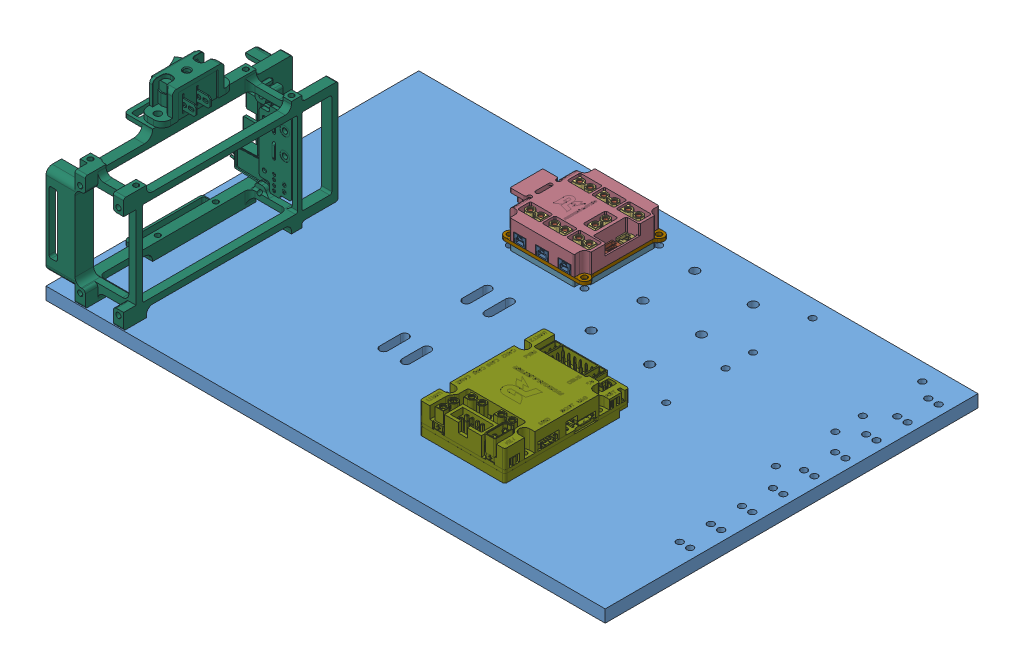
SolidWorks assembly 电气板, configuration 默认. Lengths in mm.
Overall size (270 75.31 180).
56 component instances, 16 part files, 9 mates.
Components (placement in the parent):
- 底板-2: 底板 [Default] at (214.7174 89.9924 227.1815) size (270 6 180)
- RM_ESC_Center_Board2.stp-1: RM_ESC_Center_Board2.stp [Default] at (192.7174 98.9924 170.1815) x (0 0 1) z (-1 0 0) size (41 14.11 48.51)
  - XT30UPB-F_3D_DRAWING_ASM.stp-1: XT30UPB-F_3D_DRAWING_ASM.stp [Default] at (-11.9 1.6 11.7) x (0 0 -1) z (0 1 0) size (10.2 5.6 12.4)
    - XT30UPB-F_ASM.stp-1: XT30UPB-F_ASM.stp [Default] at origin size (10.2 5.6 12.4)
      - MR30PB-F__.stp-1: MR30PB-F__.stp [Default] at (-2.5 0 7.9) x (-0.575428 -0.817853 0) z (0 0 -1) size (2.5 2.51 11.9)
      - XT30UPB-F_SJ.stp-1: XT30UPB-F_SJ.stp [Default] at origin size (10.2 5.6 9.4)
      - MR30PB-F__.stp-2: MR30PB-F__.stp [Default] at (2.5 0 7.9) x (-0.681294 -0.73201 0) z (0 0 -1) size (2.5 2.51 11.9)
  - XT30UPB-F_3D_DRAWING_ASM.stp-2: XT30UPB-F_3D_DRAWING_ASM.stp [Default] at (-11.9 1.6 0) x (0 0 -1) z (0 1 0) size (10.2 5.6 12.4)
    - XT30UPB-F_ASM.stp-1: XT30UPB-F_ASM.stp [Default] at origin size (10.2 5.6 12.4)
      - MR30PB-F__.stp-1: MR30PB-F__.stp [Default] at (-2.5 0 7.9) x (-0.575428 -0.817853 0) z (0 0 -1) size (2.5 2.51 11.9)
      - XT30UPB-F_SJ.stp-1: XT30UPB-F_SJ.stp [Default] at origin size (10.2 5.6 9.4)
      - MR30PB-F__.stp-2: MR30PB-F__.stp [Default] at (2.5 0 7.9) x (-0.681294 -0.73201 0) z (0 0 -1) size (2.5 2.51 11.9)
  - XT30UPB-F_3D_DRAWING_ASM.stp-3: XT30UPB-F_3D_DRAWING_ASM.stp [Default] at (-11.9 1.6 -11.7) x (0 0 -1) z (0 1 0) size (10.2 5.6 12.4)
    - XT30UPB-F_ASM.stp-1: XT30UPB-F_ASM.stp [Default] at origin size (10.2 5.6 12.4)
      - MR30PB-F__.stp-1: MR30PB-F__.stp [Default] at (-2.5 0 7.9) x (-0.575428 -0.817853 0) z (0 0 -1) size (2.5 2.51 11.9)
      - XT30UPB-F_SJ.stp-1: XT30UPB-F_SJ.stp [Default] at origin size (10.2 5.6 9.4)
      - MR30PB-F__.stp-2: MR30PB-F__.stp [Default] at (2.5 0 7.9) x (-0.681294 -0.73201 0) z (0 0 -1) size (2.5 2.51 11.9)
  - XT30UPB-F_3D_DRAWING_ASM.stp-4: XT30UPB-F_3D_DRAWING_ASM.stp [Default] at (11.9 1.6 11.7) x (0 0 1) z (0 1 0) size (10.2 5.6 12.4)
    - XT30UPB-F_ASM.stp-1: XT30UPB-F_ASM.stp [Default] at origin size (10.2 5.6 12.4)
      - MR30PB-F__.stp-1: MR30PB-F__.stp [Default] at (-2.5 0 7.9) x (-0.575428 -0.817853 0) z (0 0 -1) size (2.5 2.51 11.9)
      - XT30UPB-F_SJ.stp-1: XT30UPB-F_SJ.stp [Default] at origin size (10.2 5.6 9.4)
      - MR30PB-F__.stp-2: MR30PB-F__.stp [Default] at (2.5 0 7.9) x (-0.681294 -0.73201 0) z (0 0 -1) size (2.5 2.51 11.9)
  - XT30UPB-F_3D_DRAWING_ASM.stp-5: XT30UPB-F_3D_DRAWING_ASM.stp [Default] at (11.9 1.6 0) x (0 0 1) z (0 1 0) size (10.2 5.6 12.4)
    - XT30UPB-F_ASM.stp-1: XT30UPB-F_ASM.stp [Default] at origin size (10.2 5.6 12.4)
      - MR30PB-F__.stp-1: MR30PB-F__.stp [Default] at (-2.5 0 7.9) x (-0.575428 -0.817853 0) z (0 0 -1) size (2.5 2.51 11.9)
      - XT30UPB-F_SJ.stp-1: XT30UPB-F_SJ.stp [Default] at origin size (10.2 5.6 9.4)
      - MR30PB-F__.stp-2: MR30PB-F__.stp [Default] at (2.5 0 7.9) x (-0.681294 -0.73201 0) z (0 0 -1) size (2.5 2.51 11.9)
  - XT30UPB-F_3D_DRAWING_ASM.stp-6: XT30UPB-F_3D_DRAWING_ASM.stp [Default] at (11.9 1.6 -11.7) x (0 0 1) z (0 1 0) size (10.2 5.6 12.4)
    - XT30UPB-F_ASM.stp-1: XT30UPB-F_ASM.stp [Default] at origin size (10.2 5.6 12.4)
      - MR30PB-F__.stp-1: MR30PB-F__.stp [Default] at (-2.5 0 7.9) x (-0.575428 -0.817853 0) z (0 0 -1) size (2.5 2.51 11.9)
      - XT30UPB-F_SJ.stp-1: XT30UPB-F_SJ.stp [Default] at origin size (10.2 5.6 9.4)
      - MR30PB-F__.stp-2: MR30PB-F__.stp [Default] at (2.5 0 7.9) x (-0.681294 -0.73201 0) z (0 0 -1) size (2.5 2.51 11.9)
  - XT60_____ASM.stp-1: XT60_____ASM.stp [Default] at (0 5.65 40.6279) x (-1 0 0) z (0 0 -1) size (15.9 10.5 18.64)
    - XT60____-8________-2-SOLID1.stp-1: XT60____-8________-2-SOLID1.stp [Default] at origin size (0.5 9.4 2.2)
    - XT60____-8____-21157-2-SOLID1.stp-1: XT60____-8____-21157-2-SOLID1.stp [Default] at origin size (4.3 8.5 17.06)
    - XT60____-8______-UL-21156-1-SOL.stp-1: XT60____-8______-UL-21156-1-SOL.stp [Default] at origin size (15.9 8.45 18.2)
    - XT60____-8____-21157-1-SOLID1.stp-1: XT60____-8____-21157-1-SOLID1.stp [Default] at origin size (4.3 8.5 17.06)
    - XT60____-8________-1-SOLID1.stp-1: XT60____-8________-1-SOLID1.stp [Default] at origin size (0.5 9.4 2.2)
  - XT30UPB-F_3D_DRAWING_ASM.stp-7: XT30UPB-F_3D_DRAWING_ASM.stp [Default] at (0 1.6 -7.7) x (-1 0 0) z (0 1 0) size (10.2 5.6 12.4)
    - XT30UPB-F_ASM.stp-1: XT30UPB-F_ASM.stp [Default] at origin size (10.2 5.6 12.4)
      - MR30PB-F__.stp-1: MR30PB-F__.stp [Default] at (-2.5 0 7.9) x (-0.575428 -0.817853 0) z (0 0 -1) size (2.5 2.51 11.9)
      - XT30UPB-F_SJ.stp-1: XT30UPB-F_SJ.stp [Default] at origin size (10.2 5.6 9.4)
      - MR30PB-F__.stp-2: MR30PB-F__.stp [Default] at (2.5 0 7.9) x (-0.681294 -0.73201 0) z (0 0 -1) size (2.5 2.51 11.9)
  - CENTER_DISTRIBUTION_BOARD.stp-1: CENTER_DISTRIBUTION_BOARD.stp [Default] at origin size (41 1.62 41)
  - SM02B-GHS-TB.stp-1: SM02B-GHS-TB.stp [Default] at (-16.45 1.6 13.625) x (0 0 1) z (-1 0 0) size (5.75 4.35 4.85)
  - SM02B-GHS-TB.stp-2: SM02B-GHS-TB.stp [Default] at (-16.45 1.6 2.875) x (0 0 1) z (-1 0 0) size (5.75 4.35 4.85)
  - SM02B-GHS-TB.stp-3: SM02B-GHS-TB.stp [Default] at (-16.45 1.6 -7.875) x (0 0 1) z (-1 0 0) size (5.75 4.35 4.85)
  - SM02B-GHS-TB.stp-4: SM02B-GHS-TB.stp [Default] at (16.45 1.6 -13.625) x (0 0 -1) z (1 0 0) size (5.75 4.35 4.85)
  - SM02B-GHS-TB.stp-5: SM02B-GHS-TB.stp [Default] at (16.45 1.6 -2.875) x (0 0 -1) z (1 0 0) size (5.75 4.35 4.85)
  - SM02B-GHS-TB.stp-6: SM02B-GHS-TB.stp [Default] at (16.45 1.6 7.875) x (0 0 -1) z (1 0 0) size (5.75 4.35 4.85)
  - BM04B-GHS-TBT.stp-1: BM04B-GHS-TBT.stp [Default] at (7.5 1.775 -16.775) size (8.25 4.2 4.95)
  - BM02B-GHS-TBT.stp-1: BM02B-GHS-TBT.stp [Default] at (-1.75 1.775 -16.775) size (5.75 4.2 4.95)
  - SHELL_UP.stp-1: SHELL_UP.stp [Default] at (0 11.1 0.005) x (0 0 -1) z (-1 0 0) size (46.5 11.16 41)
  - SHELL_DOWN.stp-1: SHELL_DOWN.stp [Default] at (0 5 0.005) size (41 3 37)
- RoboMaster 电池架.step-1: RoboMaster 电池架.step [Default] at (90.2174 123.6924 311.1815) x (0 0 -1) z (0 1 0) size (103.5 37.5 69.31)
- mounting_the_board_type_c_asm(202001072134)-1: mounting_the_board_type_c_asm(202001072134) [Default] at (277.3177 116.5924 280.8614) x (1 0 0) z (0 1 0) size (41.04 60.33 16.3)
Mates (geometry in assembly coordinates):
- Coincident1: coincident anti-aligned: plane of 底板-2 through (214.7174 95.9924 227.1815) normal (0 1 0); plane of RM_ESC_Center_Board2.stp-1/SHELL_DOWN.stp-1 through (192.7124 95.9924 170.1815) normal (0 -1 0)
- Coincident2: coincident anti-aligned: plane of 底板-2 through (214.7174 95.9924 227.1815) normal (0 1 0); plane of RoboMaster 电池架.step-1 through (117.2174 95.9924 321.0516) normal (0 -1 0)
- Coincident3: coincident aligned: plane of 底板-2 through (79.7174 95.9924 317.1815) normal (-1 0 0); plane of RoboMaster 电池架.step-1 through (79.7174 123.6924 265.6815) normal (-1 0 0)
- Coincident4: coincident aligned: plane of 底板-2 through (349.7174 95.9924 317.1815) normal (0 0 1); plane of RoboMaster 电池架.step-1 through (103.7174 123.6924 317.1815) normal (0 0 1)
- Coincident5: coincident anti-aligned: plane of 底板-2 through (214.7174 95.9924 227.1815) normal (0 1 0); plane of mounting_the_board_type_c_asm(202001072134)-1 through (252.7173 95.9924 259.1816) normal (0 -1 0)
- Concentric1: concentric anti-aligned: cylinder of 底板-2 through (210.7174 99.9924 152.1815) axis (0 -1 0) radius 1.6; cylinder of RM_ESC_Center_Board2.stp-1/CENTER_DISTRIBUTION_BOARD.stp-1 through (210.7174 100.5924 152.1815) axis (0 1 0) radius 1.35
- Concentric2: concentric anti-aligned: cylinder of 底板-2 through (174.7174 99.9924 152.1815) axis (0 -1 0) radius 1.6; cylinder of RM_ESC_Center_Board2.stp-1/CENTER_DISTRIBUTION_BOARD.stp-1 through (174.7174 100.5924 152.1815) axis (0 1 0) radius 1.35
- Concentric3: concentric aligned: cylinder of 底板-2 through (270.7173 89.9924 241.1816) axis (0 1 0) radius 1.6; cylinder of mounting_the_board_type_c_asm(202001072134)-1 through (270.7173 95.9924 241.1816) axis (0 1 0) radius 1.25
- Concentric4: concentric aligned: cylinder of 底板-2 through (234.7174 89.9924 277.1815) axis (0 1 0) radius 1.6; cylinder of mounting_the_board_type_c_asm(202001072134)-1 through (234.7173 95.9924 277.1816) axis (0 1 0) radius 1.25
